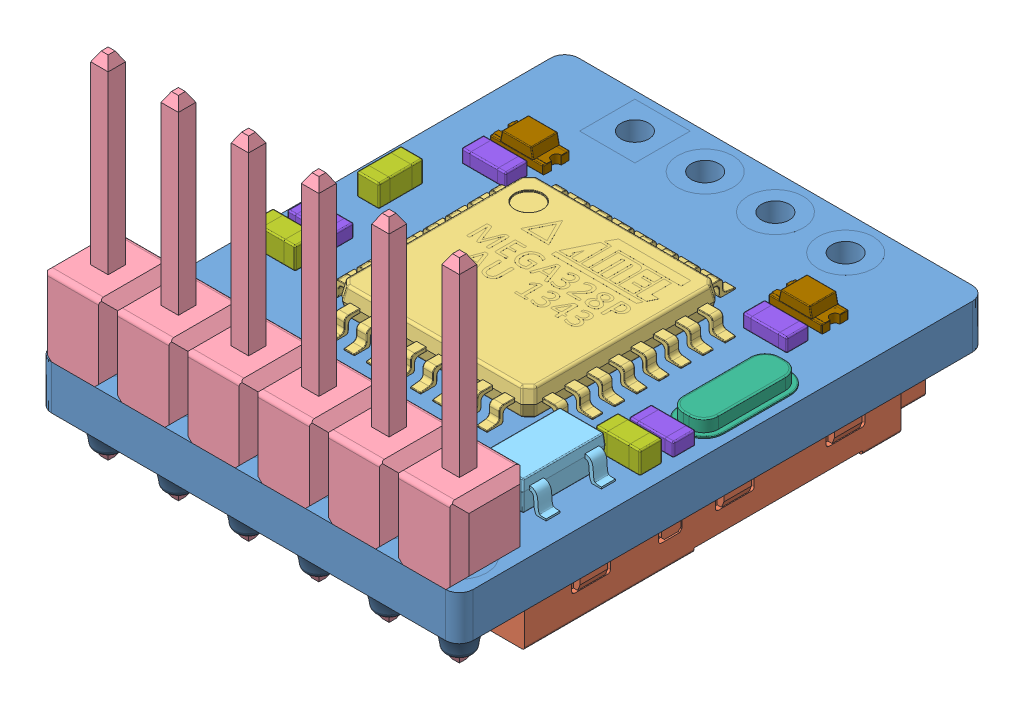
SolidWorks assembly OpenLog - pins up, configuration Default. Lengths in mm.
Overall size (15.24 12.94 19.05).
21 component instances, 10 part files, 45 mates.
Components (placement in the parent):
- OpenLog_PCB-1: OpenLog_PCB [Default] at origin size (15.24 1.6 19.05)
- microSDslot.stp-1: microSDslot.stp [Default] at (0.0152 -0.85 -1.0043) x (1 0 0) z (0 -1 0) size (14.1 15.2 1.88)
- ATmega-1: ATmega [Default] at (-0.0317 1.6 -0.6354) size (9 1.1 9)
- Pin Header 1x6 TH Pitch 2.54mm-1: Pin Header 1x6 TH Pitch 2.54mm [Default] at (6.3504 1.5986 8.255) x (-1 0 0) z (0 1 0) size (15.24 2.54 12.7)
- SOT23-5-1: SOT23-5 [Default] at (5.3808 1.495 4.313) x (-1 0 0) z (0 1 0) size (2.91 3.01 1.23)
- Fusion001-1: Fusion001 [Default] at (6.4694 1.6 -1.5764) x (0 0 -1) z (0 1 0) size (3.84 1.66 0.85)
- cap_603-1: cap_603 [Default] at (7.1016 2.4 2.4707) x (-1 0 0) z (0 0 1) size (1.6 0.8 0.8)
- res_603-1: res_603 [Default] at (7.1399 2.1 1.3029) x (-1 0 0) z (0 0 1) size (1.6 0.5 0.8)
- cap_603-2: cap_603 [Default] at (-7.1409 1.6 2.3005) size (1.6 0.8 0.8)
- res_603-2: res_603 [Default] at (-5.9255 1.6 -4.0991) size (1.6 0.5 0.8)
- res_603-3: res_603 [Default] at (4.3139 1.6 -4.0229) size (1.6 0.5 0.8)
- res_603-4: res_603 [Default] at (-5.5292 2.1 0.9961) x (-1 0 0) z (0 0 1) size (1.6 0.5 0.8)
- Surface Mount Chip LED 3.2x1.6mm-1: Surface Mount Chip LED 3.2x1.6mm [Default] at (4.0264 1.606 -5.2554) x (1 0 0) z (0 1 0) size (1.92 0.96 0.72)
- Surface Mount Chip LED 3.2x1.6mm-2: Surface Mount Chip LED 3.2x1.6mm [Default] at (-4.0759 1.606 -6.1626) x (-1 0 0) z (0 1 0) size (1.92 0.96 0.72)
- cap_603-3: cap_603 [Default] at (-6.7814 2.4 -1.167) x (0 0 -1) z (-1 0 0) size (1.6 0.8 0.8)
- solder-5: solder [Default] at (-6.35 0 8.255) x (1 0 0) z (0 0 -1) size (1.8 1.3 1.8)
- solder-7: solder [Default] at (-3.81 0 8.255) x (1 0 0) z (0 0 -1) size (1.8 1.3 1.8)
- solder-8: solder [Default] at (-1.27 0 8.255) x (1 0 0) z (0 0 -1) size (1.8 1.3 1.8)
- solder-9: solder [Default] at (1.27 0 8.255) x (1 0 0) z (0 0 -1) size (1.8 1.3 1.8)
- solder-10: solder [Default] at (3.81 0 8.255) x (1 0 0) z (0 0 -1) size (1.8 1.3 1.8)
- solder-11: solder [Default] at (6.35 0 8.255) x (1 0 0) z (0 0 -1) size (1.8 1.3 1.8)
Mates (geometry in assembly coordinates):
- Coincident1: coincident aligned: plane of OpenLog_PCB-1 through (0 0 0) normal (0 0 1)
- Coincident3: coincident aligned: plane of OpenLog_PCB-1 through (0 0 0) normal (1 0 0)
- Coincident4: coincident aligned: plane of OpenLog_PCB-1 through (0 0 0) normal (0 1 0)
- Coincident8: coincident anti-aligned: plane of OpenLog_PCB-1 through (0 0 0) normal (0 -1 0); plane of microSDslot.stp-1 through (0.0152 0 -1.0043) normal (0 1 0)
- Coincident9: coincident anti-aligned: plane of OpenLog_PCB-1 through (0 1.6 0) normal (0 1 0); plane of ATmega-1 through (-0.0317 1.6 -0.6354) normal (0 -1 0)
- Coincident11: coincident anti-aligned: plane of OpenLog_PCB-1 through (0 1.6 0) normal (0 1 0); plane of SOT23-5-1 through (4.6183 1.6 2.813) normal (0 -1 0)
- Parallel3: parallel anti-aligned: line of SOT23-5-1 through (4.5557 2.3233 2.8628) axis (0 0 1); line of OpenLog_PCB-1 through (7.62 1.6 9.025) axis (0 0 -1)
- Coincident13: coincident anti-aligned: plane of OpenLog_PCB-1 through (0 1.6 0) normal (0 1 0); plane of Fusion001-1 through (5.6557 1.6 0.3311) normal (0 -1 0)
- Parallel4: parallel anti-aligned: plane of OpenLog_PCB-1 through (7.62 1.6 -9.525) normal (1 0 0); plane of Fusion001-1 through (5.8394 1.66 0.1649) normal (-1 0 0)
- Coincident15: coincident anti-aligned: plane of OpenLog_PCB-1 through (0 1.6 0) normal (0 1 0); plane of cap_603-1 through (7.1016 1.6 2.4707) normal (0 -1 0)
- Parallel5: parallel aligned: plane of OpenLog_PCB-1 through (-7.62 1.6 -9.525) normal (-1 0 0); plane of cap_603-1 through (5.5016 1.6 1.6707) normal (-1 0 0)
- Coincident17: coincident anti-aligned: plane of OpenLog_PCB-1 through (0 1.6 0) normal (0 1 0); plane of res_603-1 through (7.1399 1.6 1.3029) normal (0 -1 0)
- Parallel6: parallel aligned: plane of OpenLog_PCB-1 through (-7.62 1.6 -9.525) normal (-1 0 0); plane of res_603-1 through (5.5399 1.6 0.5029) normal (-1 0 0)
- Coincident191: coincident anti-aligned: plane of OpenLog_PCB-1 through (0 1.6 0) normal (0 1 0); plane of cap_603-2 through (-7.1409 1.6 2.3005) normal (0 -1 0)
- Coincident201: coincident anti-aligned: plane of OpenLog_PCB-1 through (0 1.6 0) normal (0 1 0); plane of res_603-2 through (-5.9255 1.6 -4.0991) normal (0 -1 0)
- Parallel7: parallel aligned: plane of OpenLog_PCB-1 through (-7.62 1.6 -9.525) normal (-1 0 0); plane of res_603-2 through (-5.9255 2.1 -4.0991) normal (-1 0 0)
- Parallel8: parallel aligned: plane of OpenLog_PCB-1 through (-7.62 1.6 -9.525) normal (-1 0 0); plane of cap_603-2 through (-7.1409 2.4 2.3005) normal (-1 0 0)
- Lock1: lock: unknown of OpenLog_PCB-1; unknown of ATmega-1
- Coincident261: coincident anti-aligned: plane of OpenLog_PCB-1 through (0 1.6 0) normal (0 1 0); plane of res_603-4 through (-5.5292 1.6 0.9961) normal (0 -1 0)
- Parallel10: parallel aligned: plane of OpenLog_PCB-1 through (-7.62 1.6 -9.525) normal (-1 0 0); plane of res_603-4 through (-7.1292 1.6 0.1961) normal (-1 0 0)
- Coincident28: coincident anti-aligned: plane of OpenLog_PCB-1 through (0 1.6 0) normal (0 1 0); plane of Surface Mount Chip LED 3.2x1.6mm-1 through (4.8664 1.6 -6.2154) normal (0 -1 0)
- Parallel12: parallel aligned: plane of OpenLog_PCB-1 through (-7.62 1.6 -9.525) normal (-1 0 0); plane of Surface Mount Chip LED 3.2x1.6mm-2 through (-5.9959 1.606 -6.1626) normal (-1 0 0)
- Coincident31: coincident anti-aligned: plane of OpenLog_PCB-1 through (0 1.6 0) normal (0 1 0); plane of Surface Mount Chip LED 3.2x1.6mm-2 through (-4.9159 1.6 -5.2026) normal (0 -1 0)
- Coincident321: coincident anti-aligned: plane of OpenLog_PCB-1 through (0 1.6 0) normal (0 1 0); plane of cap_603-3 through (-6.7814 1.6 -1.167) normal (0 -1 0)
- Parallel13: parallel aligned: plane of OpenLog_PCB-1 through (-7.62 1.6 -9.525) normal (0 0 -1); plane of cap_603-3 through (-5.9814 1.6 -2.767) normal (0 0 -1)
- Lock9: lock: unknown of OpenLog_PCB-1; unknown of cap_603-2
- Lock10: lock: unknown of OpenLog_PCB-1; unknown of res_603-4
- Lock11: lock: unknown of OpenLog_PCB-1; unknown of cap_603-3
- Lock12: lock: unknown of OpenLog_PCB-1; unknown of res_603-2
- Lock13: lock: unknown of OpenLog_PCB-1; unknown of Surface Mount Chip LED 3.2x1.6mm-2
- Lock14: lock: unknown of OpenLog_PCB-1; unknown of Surface Mount Chip LED 3.2x1.6mm-1
- Parallel17: parallel anti-aligned: plane of OpenLog_PCB-1 through (0 1.6 0) normal (0 1 0); plane of res_603-3 through (4.3139 1.6 -4.0229) normal (0 -1 0)
- Coincident47: coincident anti-aligned: plane of OpenLog_PCB-1 through (0 1.6 0) normal (0 1 0); plane of res_603-3 through (4.3139 1.6 -4.0229) normal (0 -1 0)
- Lock15: lock: unknown of OpenLog_PCB-1; unknown of res_603-3
- Lock16: lock: unknown of OpenLog_PCB-1; unknown of Fusion001-1
- Lock17: lock: unknown of OpenLog_PCB-1; unknown of res_603-1
- Lock18: lock: unknown of OpenLog_PCB-1; unknown of cap_603-1
- Lock19: lock: unknown of OpenLog_PCB-1; unknown of SOT23-5-1
- Lock21: lock: unknown of OpenLog_PCB-1; unknown of microSDslot.stp-1
- Coincident322: coincident anti-aligned: plane of OpenLog_PCB-1 through (0 1.6 0) normal (0 1 0); plane of Pin Header 1x6 TH Pitch 2.54mm-1 through (-5.5525 1.6 6.975) normal (0 -1 0)
- Coincident324: coincident aligned: plane of OpenLog_PCB-1 through (-7.62 1.6 9.525) normal (0 0 1); plane of Pin Header 1x6 TH Pitch 2.54mm-1 through (-5.4066 1.572 9.525) normal (0 0 1)
- Coincident325: coincident anti-aligned: plane of OpenLog_PCB-1 through (0 0 0) normal (0 -1 0); plane of solder-5 through (-6.35 0 8.255) normal (0 1 0)
- Concentric1: concentric aligned: circle of OpenLog_PCB-1; circle of solder-5
- Parallel18: parallel anti-aligned: plane of OpenLog_PCB-1 through (-7.62 1.6 -9.525) normal (-1 0 0); plane of solder-5 through (-6.35 0 8.255) normal (1 0 0)
- Coincident328: coincident: plane of OpenLog_PCB-1 through (7.62 1.6 -9.525) normal (1 0 0); line of Pin Header 1x6 TH Pitch 2.54mm-1 through (7.62 2.088 7.3305) axis (0 0 1)
